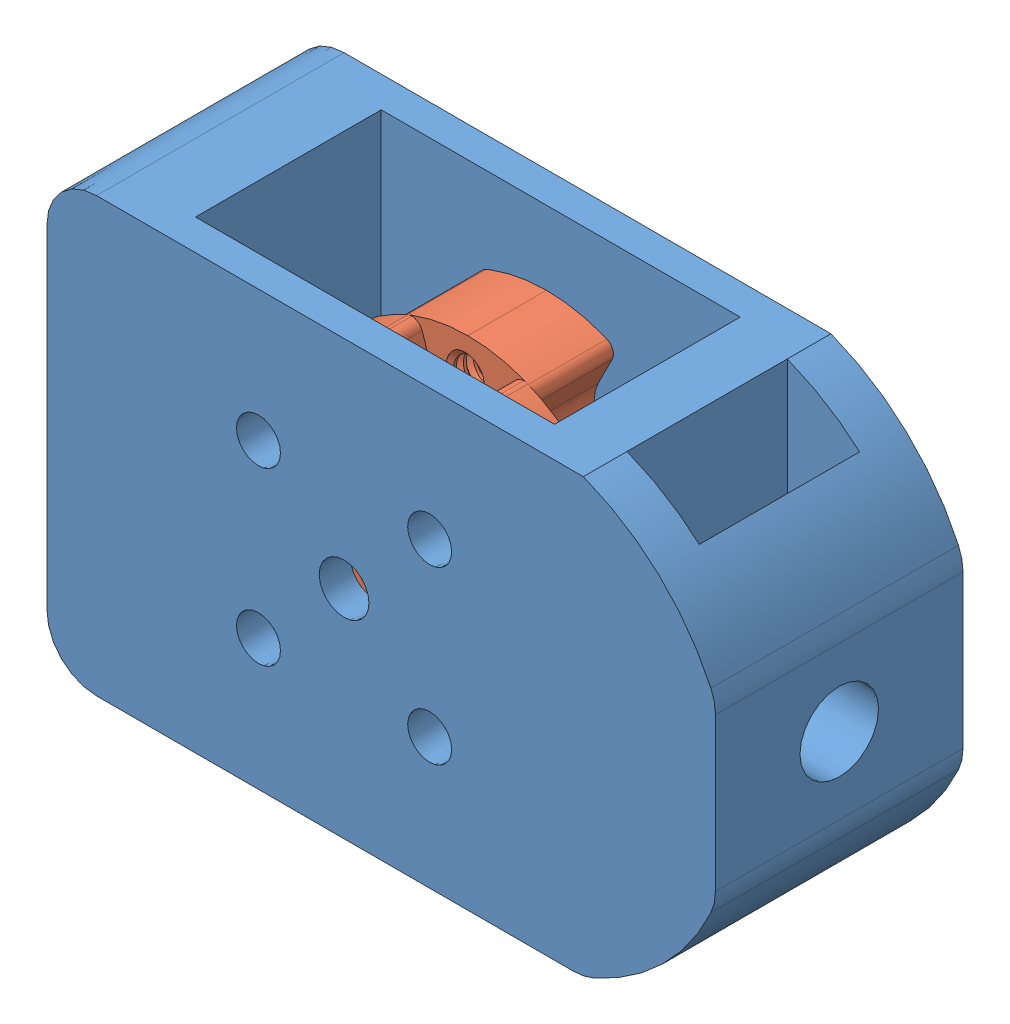
SolidWorks assembly ARMUS-101-200, configuration Défaut. Lengths in mm.
Overall size (54 35 20).
3 component instances, 3 part files, 9 mates.
Components (placement in the parent):
- ARMUS-101-201-1: ARMUS-101-201 [Défaut] at origin size (54 35 20)
- HUB-0_25-1: HUB-0_25 [Défaut] at (-30.0172 37.5992 -6.2696) x (-1 0 0) z (0 -1 0) size (25.4 12.7 25.4)
- hex nut_ai-2: hex nut_ai [HNUT 0.2500-20-D-N] at (19.3798 17.5 0) x (0 0.5 0.866025) z (-1 0 0) (suppressed, hidden)
Mates (geometry in assembly coordinates):
- Coïncidente1: coordinate: point of ARMUS-REV2-003-1
- Largeur2: width anti-aligned: plane of ARMUS-REV2-003-1 through (14.5 0 7.5) normal (0 0 -1); plane of ARMUS-REV2-003-1 through (14.5 0 -7.5) normal (0 0 1); plane of HUB-0_25-1 through (0 17.5 6.35) normal (0 0 1); plane of HUB-0_25-1 through (0 17.5 -6.35) normal (0 0 -1)
- Largeur3: width aligned: plane of ARMUS-REV2-003-1 through (0 35 0) normal (0 1 0); plane of ARMUS-REV2-003-1 through (0 0 0) normal (0 -1 0); plane of HNUT 0.2500-20-D-N-1 through (25.1202 23.0562 3.2079) normal (0 1 0); plane of HNUT 0.2500-20-D-N-1 through (25.1202 11.9437 -3.2079) normal (0 -1 0)
- Largeur4: width: plane of ARMUS-REV2-003-1 through (30 35 -10) normal (0 0 -1); plane of ARMUS-REV2-003-1 through (30 35 10) normal (0 0 1); cylinder of HNUT 0.2500-20-D-N-1 through (25.1202 17.5 0) axis (-1 0 0) radius 2.5527
- Largeur5: width aligned: plane of ARMUS-REV2-003-1 through (14.5 0 7.5) normal (-1 0 0); plane of ARMUS-REV2-003-1 through (30 35 10) normal (1 0 0); plane of HNUT 0.2500-20-D-N-1 through (19.3798 23.0562 -3.2079) normal (-1 0 0); plane of HNUT 0.2500-20-D-N-1 through (25.1202 23.0562 -3.2079) normal (1 0 0)
- Largeur6: width aligned: plane of ARMUS-REV2-003-1 through (14.5 0 -7.5) normal (0 0 1); plane of HUB-0_25-1 through (14.5 0 7.5) normal (0 0 -1); plane of ARMUS-REV2-003-1 through (0 17.5 6.35) normal (0 0 1); plane of HUB-0_25-1 through (0 17.5 -6.35) normal (0 0 -1)
- Largeur7: width: plane of ARMUS-REV2-003-1 through (14.5 0 7.5) normal (-1 0 0); plane of HUB-0_25-1 through (-14.5 0 7.5) normal (1 0 0); cylinder of ARMUS-REV2-003-1 through (0 17.5 1.5875) axis (0 0 1) radius 3.175
- Parallèle1: parallel anti-aligned: plane of HUB-0_25-1 through (-30.0172 37.5992 -6.2696) normal (-1 0 0)
- Largeur8: width: plane of ARMUS-REV2-003-1 through (0 0 0) normal (0 -1 0); plane of ARMUS-REV2-003-1 through (0 35 0) normal (0 1 0); cylinder of HUB-0_25-1 through (0 17.5 1.5875) axis (0 0 1) radius 3.175
